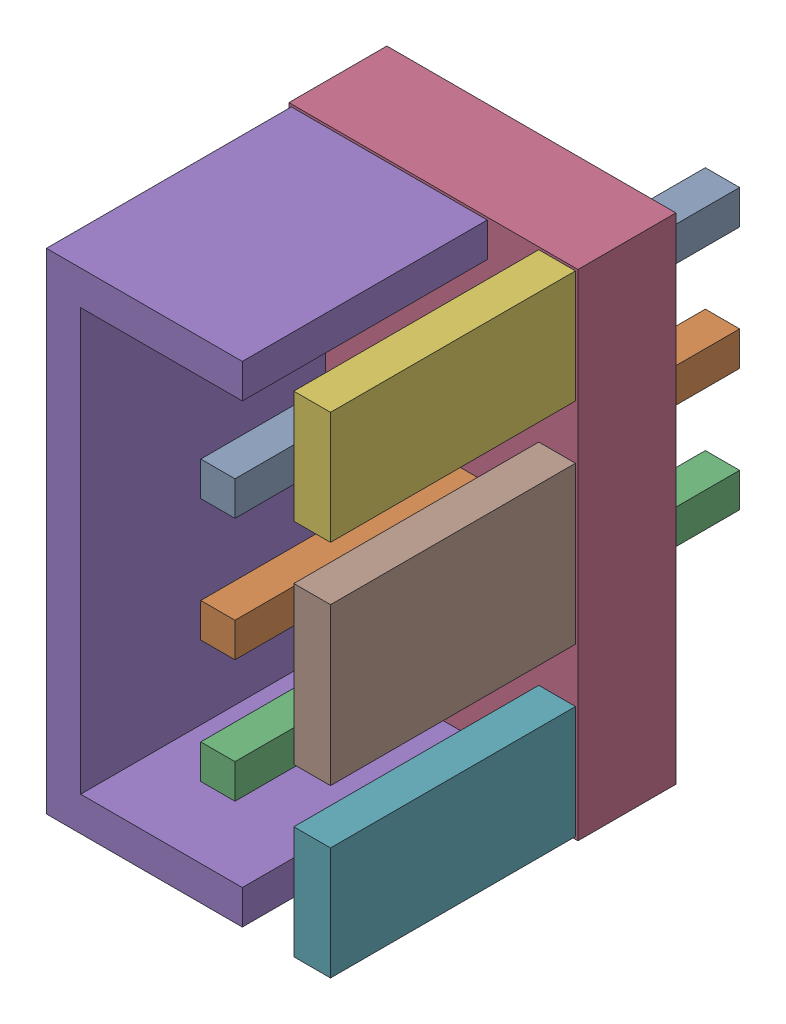
SolidWorks assembly X1, configuration По умолчанию. Lengths in mm.
Overall size (5.9 10.1 10.3).
16 component instances, 5 part files, 0 mates.
Components (placement in the parent):
- 368955840-1: 368955840 [По умолчанию] at (4.5 15 -3.2873) size (0.7 0.7 10.3)
  - Extruded_4-1: Extruded_4 [По умолчанию] at origin size (0.7 0.7 10.3)
- 368955840-2: 368955840 [По умолчанию] at (4.5 12.5 -3.2873) size (0.7 0.7 10.3)
  - Extruded_4-1: Extruded_4 [По умолчанию] at origin size (0.7 0.7 10.3)
- 368955840-3: 368955840 [По умолчанию] at (4.5 10 -3.2873) size (0.7 0.7 10.3)
  - Extruded_4-1: Extruded_4 [По умолчанию] at origin size (0.7 0.7 10.3)
- 368955968-1: 368955968 [По умолчанию] at (3.9 12.5 0.0127) size (5.9 10.1 2)
  - Extruded_5-1: Extruded_5 [По умолчанию] at origin size (5.9 10.1 2)
- 368956096-1: 368956096 [По умолчанию] at (3 12.5 0.0127) size (4 10 7)
  - Extruded_6-1: Extruded_6 [По умолчанию] at origin size (4 10 7)
- 368956224-1: 368956224 [По умолчанию] at (6.425 16.35 0.0127) size (0.75 2.3 7)
  - Extruded_7-1: Extruded_7 [По умолчанию] at origin size (0.75 2.3 7)
- 368956224-2: 368956224 [По умолчанию] at (6.425 8.65 0.0127) size (0.75 2.3 7)
  - Extruded_7-1: Extruded_7 [По умолчанию] at origin size (0.75 2.3 7)
- 368956608-1: 368956608 [По умолчанию] at (6.425 12.5 0.0127) size (0.75 3.2 7)
  - Extruded_8-1: Extruded_8 [По умолчанию] at origin size (0.75 3.2 7)
